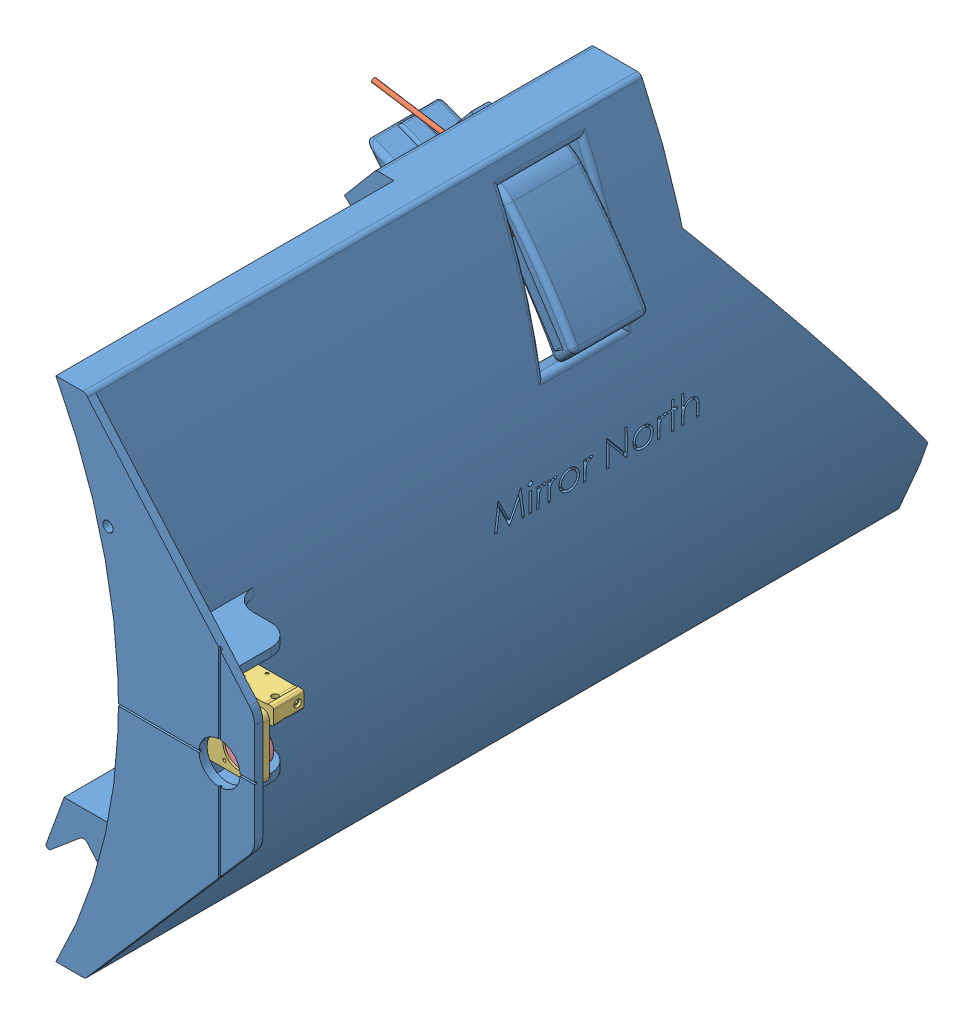
SolidWorks assembly align2_mirror_north, configuration Default. Lengths in mm.
Overall size (117.51 192.37 300).
5 component instances, 4 part files, 8 mates.
Components (placement in the parent):
- align2_mother_mirror-1: align2_mother_mirror [mirror north] at origin size (107.15 187.65 300)
- Tspring_360_LH_MC9287K143-1: Tspring_360_LH_MC9287K143 [wrap 251] at (184.7601 72.059 25.2949) x (0 0 -1) z (0.212168 -0.977233 0) size (24.67 55.31 75.8)
- align2_mother_mirror-2: align2_mother_mirror [toggle clamp] at (33.566 -56.0185 0) x (0.946067 0.323972 0) z (0 0 1) size (63.49 57.3 28.62)
- newfocus_9762-k-1: newfocus_9762-k [Default] at (223.525 15.875 153) x (0 0 1) z (0 1 0) size (16.77 23.88 23.88)
- Mirror_Thorlabs_7710_E0W_recon-1: Mirror_Thorlabs_7710_E0W_recon [Default] at (239.4 0 154.0373) x (0.923728 0.383049 0) z (0 0 -1) size (12.7 12.7 6)
Mates (geometry in assembly coordinates):
- Coincident5: coincident: cylinder of align2_mother_mirror-1 through (185.0319 72.8047 -135) axis (0 0 1) radius 0.7937; line of Tspring_360_LH_MC9287K143-1 through (184.7601 72.059 107.8261) axis (0 0 -1)
- Coincident6: coincident aligned: plane of align2_mother_mirror-2 through (33.566 -56.0185 0) normal (0 0 1); plane of assembly through (0 0 0) normal (0 0 1)
- Concentric6: concentric aligned: cylinder of align2_mother_mirror-1 through (185.0319 72.8047 -135) axis (0 0 1) radius 0.7937; cylinder of align2_mother_mirror-2 through (185.0319 72.8047 -135) axis (0 0 1) radius 0.7937
- Concentric9: concentric anti-aligned: cylinder of newfocus_9762-k-1 through (243.8545 0 157.8397) axis (0 0 -1) radius 5.9563; cylinder of Mirror_Thorlabs_7710_E0W_recon-1 through (243.8545 0 151.0373) axis (0 0 1) radius 6.35
- Coincident8: coincident anti-aligned: plane of newfocus_9762-k-1 through (243.9192 -0.0635 157.0373) normal (0 0 -1); plane of Mirror_Thorlabs_7710_E0W_recon-1 through (243.8545 0 157.0373) normal (0 0 1)
- Concentric10: concentric aligned: cylinder of align2_mother_mirror-1 through (223.525 8.255 148.936) axis (1 0 0) radius 0.8; cylinder of newfocus_9762-k-1 through (223.6977 8.255 148.936) axis (1 0 0) radius 1.143
- Concentric11: concentric aligned: cylinder of align2_mother_mirror-1 through (223.525 -4.445 148.936) axis (1 0 0) radius 0.8; cylinder of newfocus_9762-k-1 through (223.5274 -4.445 148.936) axis (1 0 0) radius 1.143
- Coincident9: coincident anti-aligned: plane of align2_mother_mirror-1 through (223.525 0 0) normal (1 0 0); plane of newfocus_9762-k-1 through (223.525 -6.5277 147.412) normal (-1 0 0)
